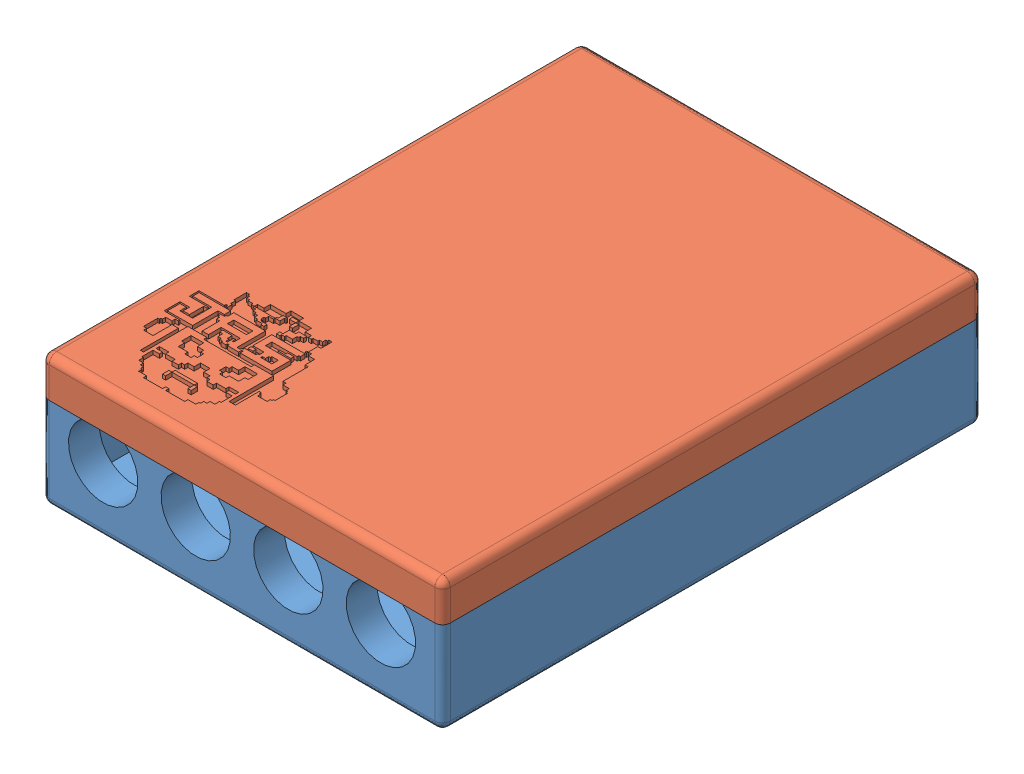
SolidWorks assembly Assem1, configuration Default. Lengths in mm.
Overall size (101.21 26.99 127.65).
2 component instances, 2 part files, 2 mates.
Components (placement in the parent):
- CaseBottom_1_2-1: CaseBottom_1_2 [Default] at (-0.1374 -6.2349 -2.8679) size (101.21 20.64 127.65)
- CaseTop_1_2-1: CaseTop_1_2 [Default] at (-0.1374 20.7526 -2.8679) x (-1 0 0) z (0 0 1) size (82.55 15.07 111.12)
Mates (geometry in assembly coordinates):
- Coincident3: coincident anti-aligned: line of CaseBottom_1_2-1 through (41.1376 12.8151 51.1071) axis (0 0 -1); line of CaseTop_1_2-1 through (41.1376 12.8151 -56.8429) axis (0 0 1)
- Coincident4: coincident anti-aligned: line of CaseBottom_1_2-1 through (-24.2044 12.8151 52.6946) axis (1 0 0); line of CaseTop_1_2-1 through (39.5501 12.8151 52.6946) axis (-1 0 0)
